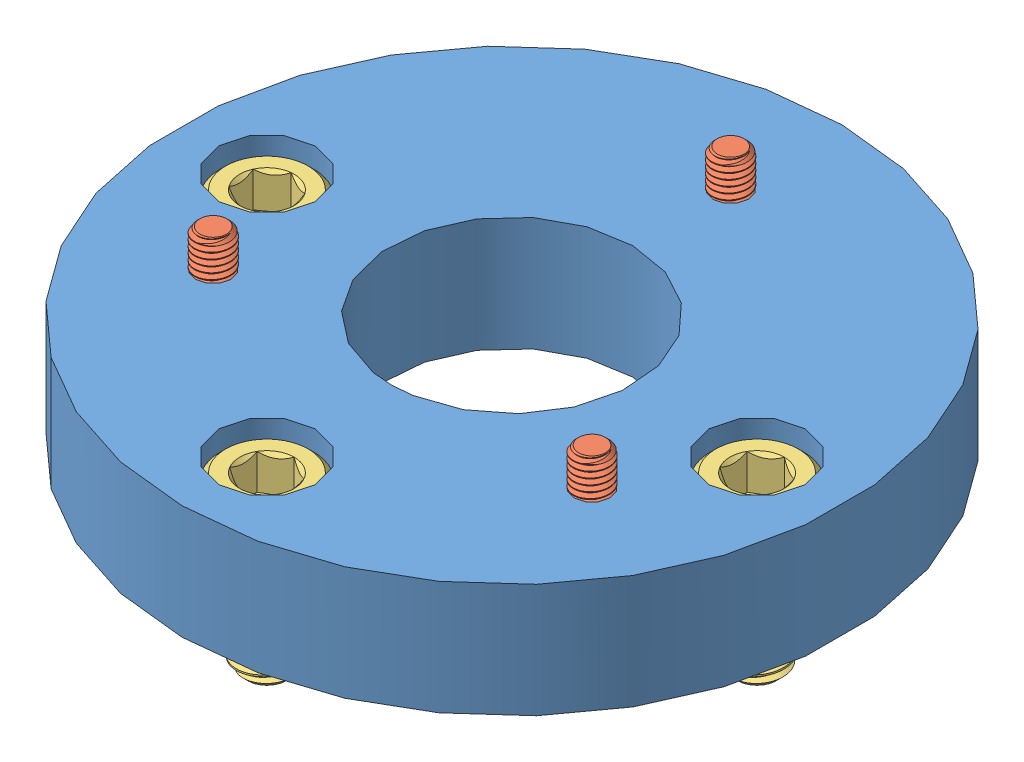
SolidWorks assembly testBuild, configuration Default. Lengths in mm.
Overall size (55.58 19.19 55.58).
7 component instances, 3 part files, 12 mates.
Components (placement in the parent):
- mountingPlate-1: mountingPlate [Default] at (13.9875 24.733 49.1248) size (55.58 9.59 55.58)
- 91294A132_BLACK ALLOY STEEL FLAT-HEAD SOCKET CAP SCREW-1: 91294A132_BLACK ALLOY STEEL FLAT-HEAD SOCKET CAP SCREW [91294A132] at (13.9875 25.433 30.7098) x (0.368055 0 0.929804) z (0 -1 0) size (6 6 12.31)
- 91294A132_BLACK ALLOY STEEL FLAT-HEAD SOCKET CAP SCREW-2: 91294A132_BLACK ALLOY STEEL FLAT-HEAD SOCKET CAP SCREW [91294A132] at (29.9354 25.433 58.3323) x (0.368055 0 0.929804) z (0 -1 0) size (6 6 12.31)
- 91294A132_BLACK ALLOY STEEL FLAT-HEAD SOCKET CAP SCREW-3: 91294A132_BLACK ALLOY STEEL FLAT-HEAD SOCKET CAP SCREW [91294A132] at (-1.9603 25.433 58.3323) x (0.107874 0 0.994165) z (0 -1 0) size (6 6 12.31)
- 91251A240_BLACK-OXIDE ALLOY STEEL SOCKET HEAD CAP SCREW-1: 91251A240_BLACK-OXIDE ALLOY STEEL SOCKET HEAD CAP SCREW [91251A240] at (13.9875 18.7965 69.7623) x (1 0 0) z (0 -1 0) size (7.92 7.92 14.93)
- 91251A240_BLACK-OXIDE ALLOY STEEL SOCKET HEAD CAP SCREW-2: 91251A240_BLACK-OXIDE ALLOY STEEL SOCKET HEAD CAP SCREW [91251A240] at (-6.65 18.7965 49.1248) x (0.406654 0 -0.913582) z (0 -1 0) size (7.92 7.92 14.93)
- 91251A240_BLACK-OXIDE ALLOY STEEL SOCKET HEAD CAP SCREW-3: 91251A240_BLACK-OXIDE ALLOY STEEL SOCKET HEAD CAP SCREW [91251A240] at (34.625 18.7965 49.1248) x (1 0 0) z (0 -1 0) size (7.92 7.92 14.93)
Mates (geometry in assembly coordinates):
- Concentric1: concentric aligned: cone of mountingPlate-1 through (13.9875 24.733 30.7098) axis (0 1 0); cone of 91294A132_BLACK ALLOY STEEL FLAT-HEAD SOCKET CAP SCREW-1 through (13.9875 27.133 30.7098) axis (0 1 0)
- Coincident2: coincident aligned: cone of mountingPlate-1 through (13.9875 24.733 30.7098) axis (0 1 0); cone of 91294A132_BLACK ALLOY STEEL FLAT-HEAD SOCKET CAP SCREW-1 through (13.9875 27.133 30.7098) axis (0 1 0)
- Concentric2: concentric aligned: cone of mountingPlate-1 through (-1.9603 24.733 58.3323) axis (0 1 0); cone of 91294A132_BLACK ALLOY STEEL FLAT-HEAD SOCKET CAP SCREW-3 through (-1.9603 27.133 58.3323) axis (0 1 0)
- Concentric3: concentric aligned: cone of mountingPlate-1 through (29.9354 24.733 58.3323) axis (0 1 0); cone of 91294A132_BLACK ALLOY STEEL FLAT-HEAD SOCKET CAP SCREW-2 through (29.9354 27.133 58.3323) axis (0 1 0)
- Coincident5: coincident aligned: cone of mountingPlate-1 through (29.9354 24.733 58.3323) axis (0 1 0); cone of 91294A132_BLACK ALLOY STEEL FLAT-HEAD SOCKET CAP SCREW-2 through (29.9354 27.133 58.3323) axis (0 1 0)
- Coincident6: coincident aligned: cone of mountingPlate-1 through (-1.9603 24.733 58.3323) axis (0 1 0); cone of 91294A132_BLACK ALLOY STEEL FLAT-HEAD SOCKET CAP SCREW-3 through (-1.9603 27.133 58.3323) axis (0 1 0)
- Concentric4: concentric anti-aligned: cylinder of mountingPlate-1 through (-6.65 24.733 49.1248) axis (0 1 0) radius 1.8387; cylinder of 91251A240_BLACK-OXIDE ALLOY STEEL SOCKET HEAD CAP SCREW-2 through (-6.65 33.1475 49.1248) axis (0 -1 0) radius 3.9624
- Concentric5: concentric anti-aligned: cylinder of mountingPlate-1 through (13.9875 24.733 69.7623) axis (0 1 0) radius 1.8387; cylinder of 91251A240_BLACK-OXIDE ALLOY STEEL SOCKET HEAD CAP SCREW-1 through (13.9875 33.1475 69.7623) axis (0 -1 0) radius 3.9624
- Concentric6: concentric anti-aligned: cylinder of mountingPlate-1 through (34.625 24.733 49.1248) axis (0 1 0) radius 1.8387; cylinder of 91251A240_BLACK-OXIDE ALLOY STEEL SOCKET HEAD CAP SCREW-3 through (34.625 33.1475 49.1248) axis (0 -1 0) radius 3.9624
- Coincident7: coincident anti-aligned: plane of mountingPlate-1 through (34.625 28.3215 49.1248) normal (0 1 0); plane of 91251A240_BLACK-OXIDE ALLOY STEEL SOCKET HEAD CAP SCREW-3 through (34.625 28.3215 49.1248) normal (0 -1 0)
- Coincident8: coincident anti-aligned: plane of mountingPlate-1 through (13.9875 28.3215 69.7623) normal (0 1 0); plane of 91251A240_BLACK-OXIDE ALLOY STEEL SOCKET HEAD CAP SCREW-1 through (13.9875 28.3215 69.7623) normal (0 -1 0)
- Coincident9: coincident anti-aligned: plane of mountingPlate-1 through (-6.65 28.3215 49.1248) normal (0 1 0); plane of 91251A240_BLACK-OXIDE ALLOY STEEL SOCKET HEAD CAP SCREW-2 through (-6.65 28.3215 49.1248) normal (0 -1 0)
